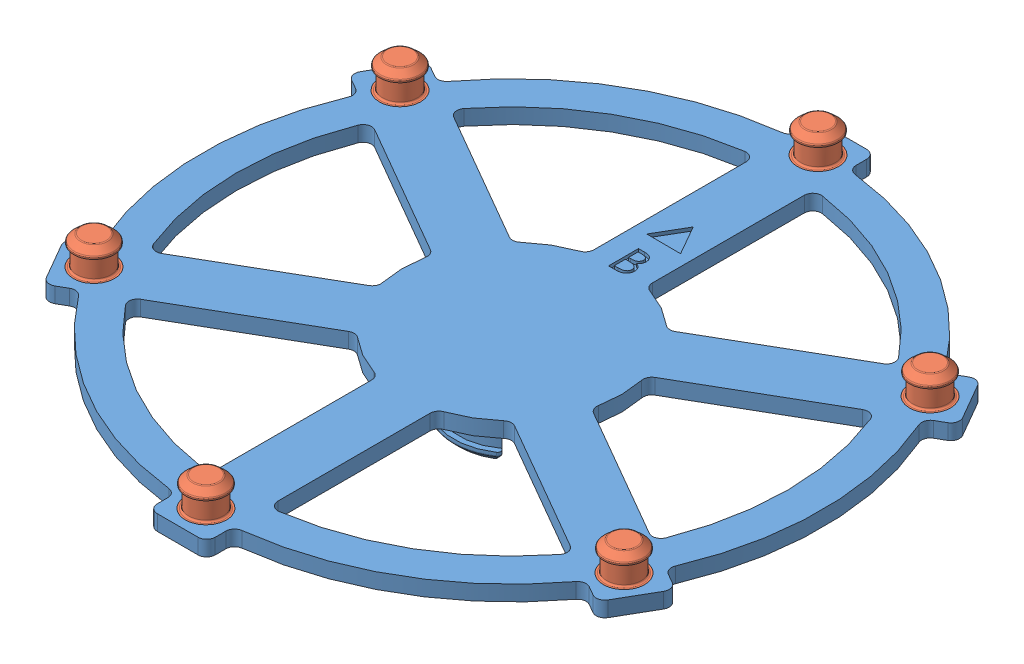
SolidWorks assembly inner_floor_big_B_plugs, configuration Default. Lengths in mm.
Overall size (83.28 14 90.16).
7 component instances, 2 part files, 12 mates.
Components (placement in the parent):
- inner_floor_big_B-1: inner_floor_big_B [Default] at (28.191 43.6201 87.4933) size (83.28 10.09 90.16)
- swivel_plug-1: swivel_plug [Default] at (-7.459 43.8807 108.0733) size (5.52 5.98 5.52)
- swivel_plug-2: swivel_plug [Default] at (28.191 43.8807 128.6559) size (5.52 5.98 5.52)
- swivel_plug-3: swivel_plug [Default] at (63.841 43.8807 108.0733) size (5.52 5.98 5.52)
- swivel_plug-4: swivel_plug [Default] at (63.841 43.8807 66.9082) size (5.52 5.98 5.52)
- swivel_plug-5: swivel_plug [Default] at (28.191 43.8807 46.3257) size (5.52 5.98 5.52)
- swivel_plug-6: swivel_plug [Default] at (-7.459 43.8807 66.9082) size (5.52 5.98 5.52)
Mates (geometry in assembly coordinates):
- Concentric1: concentric aligned: cylinder of inner_floor_big_B-1 through (-7.459 45.5933 108.0733) axis (0 -1 0) radius 2.76; cylinder of swivel_plug-1 through (-7.459 45.5933 108.0733) axis (0 -1 0) radius 2.76
- Coincident2: coincident aligned: plane of inner_floor_big_B-1 through (28.191 43.5233 87.4908) normal (0 -1 0); plane of swivel_plug-1 through (-7.459 43.5233 108.0733) normal (0 -1 0)
- Concentric2: concentric aligned: cylinder of inner_floor_big_B-1 through (28.191 45.5933 128.6559) axis (0 -1 0) radius 2.76; cylinder of swivel_plug-2 through (28.191 45.5933 128.6559) axis (0 -1 0) radius 2.76
- Coincident3: coincident aligned: plane of inner_floor_big_B-1 through (28.191 43.5233 87.4908) normal (0 -1 0); plane of swivel_plug-2 through (28.191 43.5233 128.6559) normal (0 -1 0)
- Concentric3: concentric anti-aligned: cylinder of inner_floor_big_B-1 through (63.841 45.5933 108.0733) axis (0 -1 0) radius 2.76; circle of swivel_plug-3
- Coincident4: coincident aligned: plane of inner_floor_big_B-1 through (28.191 43.5233 87.4908) normal (0 -1 0); plane of swivel_plug-3 through (63.841 43.5233 108.0733) normal (0 -1 0)
- Concentric4: concentric aligned: cylinder of inner_floor_big_B-1 through (63.841 45.5933 66.9082) axis (0 -1 0) radius 2.76; cylinder of swivel_plug-4 through (63.841 45.5933 66.9082) axis (0 -1 0) radius 2.76
- Coincident6: coincident aligned: plane of inner_floor_big_B-1 through (28.191 43.5233 87.4908) normal (0 -1 0); plane of swivel_plug-4 through (63.841 43.5233 66.9082) normal (0 -1 0)
- Concentric5: concentric aligned: cylinder of inner_floor_big_B-1 through (28.191 45.5933 46.3257) axis (0 -1 0) radius 2.76; cylinder of swivel_plug-5 through (28.191 45.5933 46.3257) axis (0 -1 0) radius 2.76
- Coincident7: coincident aligned: plane of inner_floor_big_B-1 through (28.191 43.5233 87.4908) normal (0 -1 0); plane of swivel_plug-5 through (28.191 43.5233 46.3257) normal (0 -1 0)
- Concentric6: concentric aligned: cylinder of inner_floor_big_B-1 through (-7.459 45.5933 66.9082) axis (0 -1 0) radius 2.76; cylinder of swivel_plug-6 through (-7.459 45.5933 66.9082) axis (0 -1 0) radius 2.76
- Coincident8: coincident aligned: plane of inner_floor_big_B-1 through (28.191 43.5233 87.4908) normal (0 -1 0); plane of swivel_plug-6 through (-7.459 43.5233 66.9082) normal (0 -1 0)
